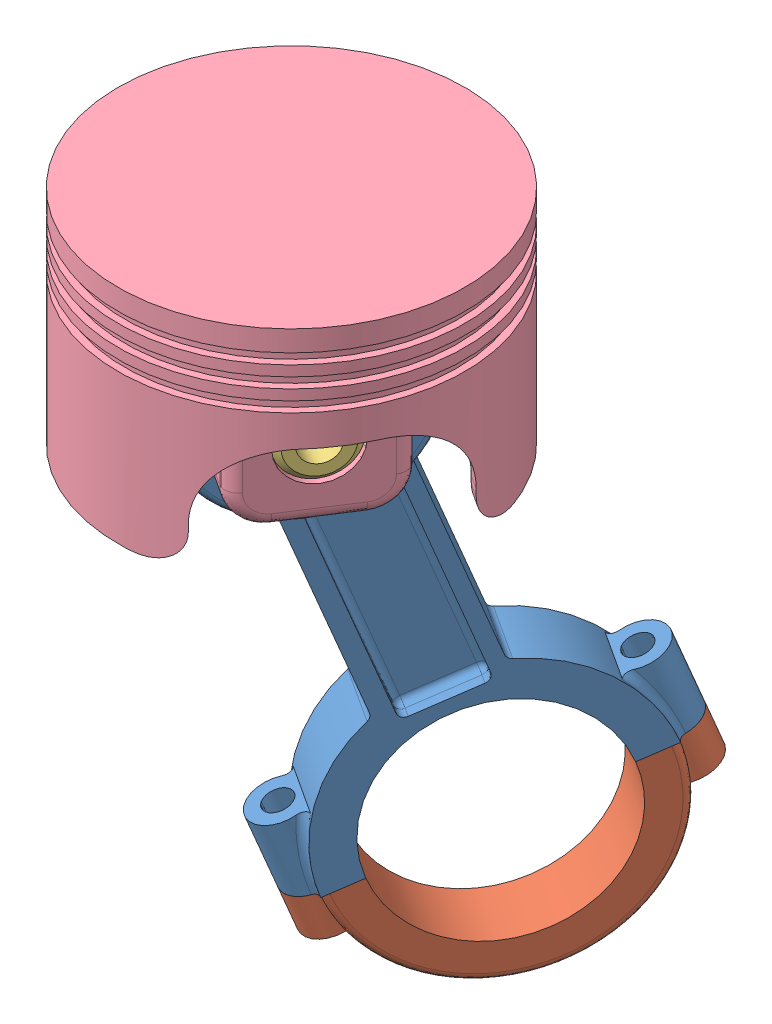
SolidWorks assembly Piston assembly, configuration Default. Lengths in mm.
Overall size (175.83 268.61 201.46).
4 component instances, 4 part files, 8 mates.
Components (placement in the parent):
- 1. piston rod-1: 1. piston rod [Default] at (-72.8947 113.817 -69.3803) x (-0.838733 0 -0.544543) z (-0.18878 0.937985 0.290769) size (32.53 120.65 190.5)
- 2. piston rod cap-1: 2. piston rod cap [Default] at (-58.5097 42.3426 -91.5369) x (-0.838733 0 -0.544543) z (-0.510773 -0.346676 0.786719) size (25.82 51.52 120.65)
- 3. Piston pin-1: 3. Piston pin [Default] at (-87.2378 185.2914 -47.1965) x (0 1 0) z (0.544543 0 -0.838733) size (25.4 69.85 25.4)
- 4. Piston head-1: 4. Piston head [Default] at (-87.2756 242.3914 -47.221) x (-0.838733 0 -0.544543) z (0.544543 0 -0.838733) size (127.19 82.5 127)
Mates (geometry in assembly coordinates):
- Concentric1: concentric: cylinder of 1. piston rod-1 through (-97.3991 185.2914 -53.7936) axis (0.838733 0 0.544543) radius 25.4; cylinder of 4. Piston head-1 through (-153.2168 185.2914 -90.033) axis (0.838733 0 0.544543) radius 12.7
- Coincident7: coincident: plane of 1. piston rod-1 through (-100.5947 185.2914 -55.8683) normal (-0.838733 0 -0.544543); plane of 4. Piston head-1 through (-86.7633 159.8914 -77.1722) normal (0.838733 0 0.544543)
- Coincident8: coincident: plane of 1. piston rod-1 through (-68.629 42.3426 -98.1068) normal (0.18878 -0.937985 -0.290769); plane of 2. piston rod cap-1 through (-94.5763 24.7314 -58.1415) normal (-0.18878 0.937985 0.290769)
- Concentric4: concentric: cylinder of 1. piston rod-1 through (-92.8388 66.3779 -38.6615) axis (0.18878 -0.937985 -0.290769) radius 4.76; circle of 2. piston rod cap-1
- Concentric5: concentric: cylinder of 3. Piston pin-1 through (-57.9451 185.2914 -28.1783) axis (-0.838733 0 -0.544543) radius 12.7; cylinder of 4. Piston head-1 through (-153.2168 185.2914 -90.033) axis (0.838733 0 0.544543) radius 12.7
- Coincident9: coincident: plane of 3. Piston pin-1 through (-116.5306 185.2914 -66.2147) normal (-0.838733 0 -0.544543); plane of 4. Piston head-1 through (-102.6992 159.8914 -87.5185) normal (-0.838733 0 -0.544543)
- Concentric6: concentric: circle of 1. piston rod-1; circle of 2. piston rod cap-1
- Parallel2: parallel: plane of 4. Piston head-1 through (-87.2756 242.3914 -47.221) normal (0 1 0); plane of assembly through (0 0 0) normal (0 1 0)
